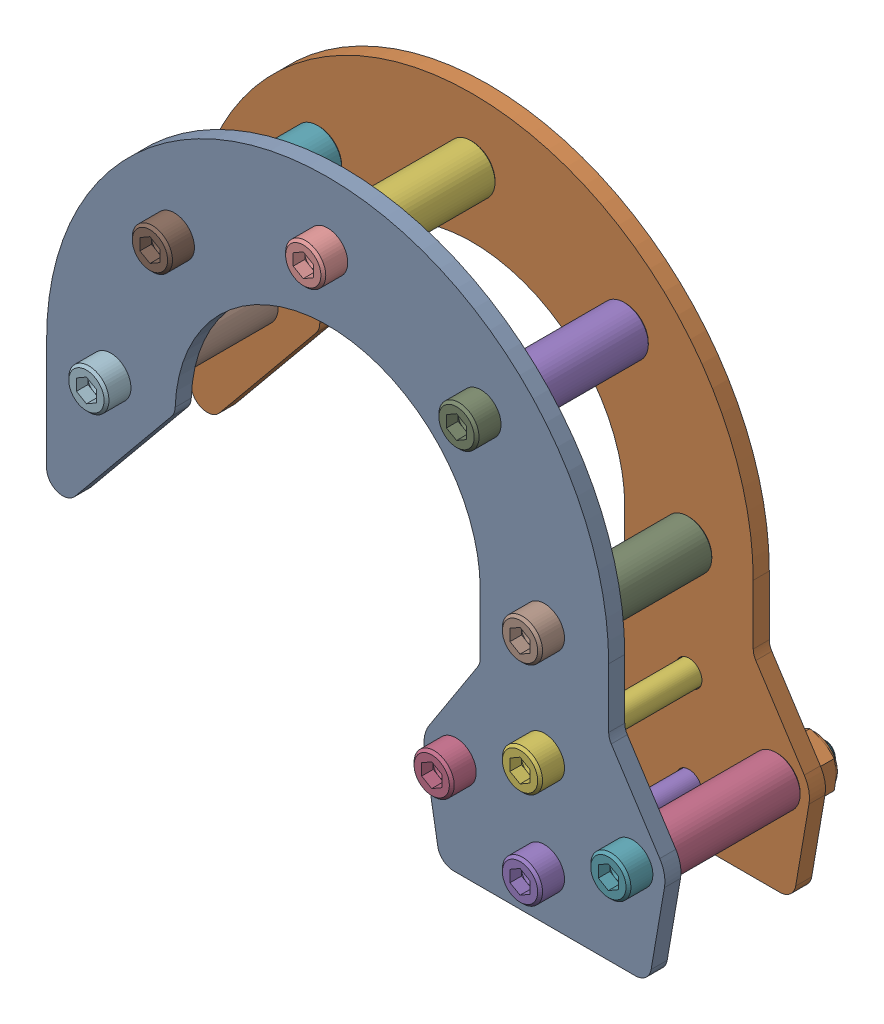
SolidWorks assembly am-4660 Climber in a Box Hook Kit_2, configuration Default. Lengths in mm.
Overall size (122.24 106.36 42.93).
27 component instances, 4 part files, 0 mates.
Components (placement in the parent):
- am-4654 Climber In A Box Hook Plate_2-1: am-4654 Climber In A Box Hook Plate_2 [Default] at (102.0153 749.012 711.9718) x (-1 0 0) z (0 -1 0) size (122.24 3.17 106.36)
- am-4654 Climber In A Box Hook Plate_2-2: am-4654 Climber In A Box Hook Plate_2 [Default] at (102.0153 749.012 683.3968) x (-1 0 0) z (0 -1 0) size (122.24 3.17 106.36)
- am-3876 1000long .192ID Aluminum Spacer_2-10: am-3876 1000long .192ID Aluminum Spacer_2 [Default] at (71.8528 768.062 708.7968) x (1 0 0) z (0 1 0) size (9.53 25.4 9.53)
- am-3876 1000long .192ID Aluminum Spacer_2-11: am-3876 1000long .192ID Aluminum Spacer_2 [Default] at (106.7778 768.062 708.7968) x (1 0 0) z (0 1 0) size (9.53 25.4 9.53)
- am-3876 1000long .192ID Aluminum Spacer_2-12: am-3876 1000long .192ID Aluminum Spacer_2 [Default] at (76.7612 830.1204 708.7968) x (1 0 0) z (0 1 0) size (9.53 25.4 9.53)
- am-3876 1000long .192ID Aluminum Spacer_2-4: am-3876 1000long .192ID Aluminum Spacer_2 [Default] at (46.4528 842.6745 708.7968) x (1 0 0) z (0 1 0) size (9.53 25.4 9.53)
- am-3876 1000long .192ID Aluminum Spacer_2-13: am-3876 1000long .192ID Aluminum Spacer_2 [Default] at (16.1445 830.1204 708.7968) x (1 0 0) z (0 1 0) size (9.53 25.4 9.53)
- am-3876 1000long .192ID Aluminum Spacer_2-14: am-3876 1000long .192ID Aluminum Spacer_2 [Default] at (3.5903 799.812 708.7968) x (1 0 0) z (0 1 0) size (9.53 25.4 9.53)
- am-3876 1000long .192ID Aluminum Spacer_2-15: am-3876 1000long .192ID Aluminum Spacer_2 [Default] at (89.3153 799.812 708.7968) x (1 0 0) z (0 1 0) size (9.53 25.4 9.53)
- 10-32 Nylock Jam Nut_90633A411_2-15: 10-32 Nylock Jam Nut_90633A411_2 [Default] at (3.5903 799.812 680.2218) x (1 0 0) z (0 1 0) size (9.55 4.38 11.02)
- 10-32 Nylock Jam Nut_90633A411_2-16: 10-32 Nylock Jam Nut_90633A411_2 [Default] at (16.1445 830.1204 680.2218) x (1 0 0) z (0 1 0) size (9.55 4.38 11.02)
- 10-32 Nylock Jam Nut_90633A411_2-17: 10-32 Nylock Jam Nut_90633A411_2 [Default] at (46.4528 842.6745 680.2218) x (1 0 0) z (0 1 0) size (9.55 4.38 11.02)
- 10-32 Nylock Jam Nut_90633A411_2-18: 10-32 Nylock Jam Nut_90633A411_2 [Default] at (76.7612 830.1204 680.2218) x (1 0 0) z (0 1 0) size (9.55 4.38 11.02)
- 10-32 Nylock Jam Nut_90633A411_2-5: 10-32 Nylock Jam Nut_90633A411_2 [Default] at (89.3153 799.812 680.2218) x (1 0 0) z (0 1 0) size (9.55 4.38 11.02)
- 10-32 Nylock Jam Nut_90633A411_2-19: 10-32 Nylock Jam Nut_90633A411_2 [Default] at (89.3153 777.587 680.2218) x (1 0 0) z (0 1 0) size (9.55 4.38 11.02)
- 10-32 Nylock Jam Nut_90633A411_2-20: 10-32 Nylock Jam Nut_90633A411_2 [Default] at (89.3153 758.537 680.2218) x (1 0 0) z (0 1 0) size (9.55 4.38 11.02)
- 10-32 Nylock Jam Nut_90633A411_2-21: 10-32 Nylock Jam Nut_90633A411_2 [Default] at (71.8528 768.062 680.2218) x (1 0 0) z (0 1 0) size (9.55 4.38 11.02)
- 10-32 Nylock Jam Nut_90633A411_2-22: 10-32 Nylock Jam Nut_90633A411_2 [Default] at (106.7778 768.062 680.2218) x (1 0 0) z (0 1 0) size (9.55 4.38 11.02)
- 10-32x1500_shcs_HX-SHCS 0.19-32x1.375x1-C_2-5: 10-32x1500_shcs_HX-SHCS 0.19-32x1.375x1-C_2 [Default] at (71.8528 768.062 716.7978) x (0 0 -1) z (1 0 0) size (42.93 7.94 7.94)
- 10-32x1500_shcs_HX-SHCS 0.19-32x1.375x1-C_2-6: 10-32x1500_shcs_HX-SHCS 0.19-32x1.375x1-C_2 [Default] at (89.3153 758.537 716.7978) x (0 0 -1) z (1 0 0) size (42.93 7.94 7.94)
- 10-32x1500_shcs_HX-SHCS 0.19-32x1.375x1-C_2-3: 10-32x1500_shcs_HX-SHCS 0.19-32x1.375x1-C_2 [Default] at (89.3153 777.587 716.7978) x (0 0 -1) z (1 0 0) size (42.93 7.94 7.94)
- 10-32x1500_shcs_HX-SHCS 0.19-32x1.375x1-C_2-7: 10-32x1500_shcs_HX-SHCS 0.19-32x1.375x1-C_2 [Default] at (106.7778 768.062 716.7978) x (0 0 -1) z (1 0 0) size (42.93 7.94 7.94)
- 10-32x1500_shcs_HX-SHCS 0.19-32x1.375x1-C_2-8: 10-32x1500_shcs_HX-SHCS 0.19-32x1.375x1-C_2 [Default] at (89.3153 799.812 716.7978) x (0 0 -1) z (1 0 0) size (42.93 7.94 7.94)
- 10-32x1500_shcs_HX-SHCS 0.19-32x1.375x1-C_2-9: 10-32x1500_shcs_HX-SHCS 0.19-32x1.375x1-C_2 [Default] at (76.7612 830.1204 716.7978) x (0 0 -1) z (1 0 0) size (42.93 7.94 7.94)
- 10-32x1500_shcs_HX-SHCS 0.19-32x1.375x1-C_2-10: 10-32x1500_shcs_HX-SHCS 0.19-32x1.375x1-C_2 [Default] at (46.4528 842.6745 716.7978) x (0 0 -1) z (1 0 0) size (42.93 7.94 7.94)
- 10-32x1500_shcs_HX-SHCS 0.19-32x1.375x1-C_2-11: 10-32x1500_shcs_HX-SHCS 0.19-32x1.375x1-C_2 [Default] at (16.1445 830.1204 716.7978) x (0 0 -1) z (1 0 0) size (42.93 7.94 7.94)
- 10-32x1500_shcs_HX-SHCS 0.19-32x1.375x1-C_2-12: 10-32x1500_shcs_HX-SHCS 0.19-32x1.375x1-C_2 [Default] at (3.5903 799.812 716.7978) x (0 0 -1) z (1 0 0) size (42.93 7.94 7.94)
